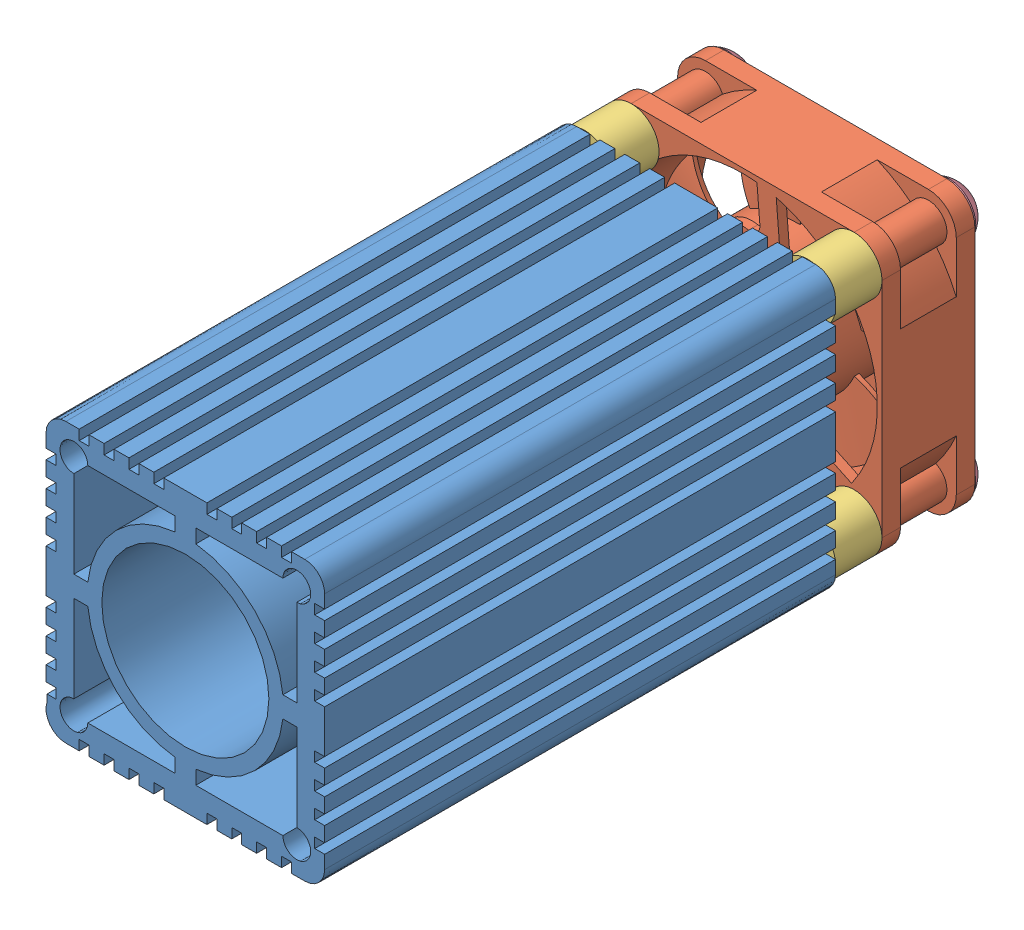
SolidWorks assembly laser host all, configuration Default. Lengths in mm.
Overall size (32.08 31.56 71.72).
10 component instances, 4 part files, 18 mates.
Components (placement in the parent):
- laser housing extrusion-1: laser housing extrusion [Default] at (39.1626 49.5405 18.2277) size (30 30 55)
- 12VDC-1.1875-X-0.375-DELTA-BOX-FAN-1: 12VDC-1.1875-X-0.375-DELTA-BOX-FAN [Default] at (39.1626 49.5405 8.2277) size (31.36 31.11 10)
- housing fan spacer-1: housing fan spacer [Default] at (27.1626 61.5405 13.2277) x (1 0 0) z (0 -1 0) size (6 5 6)
- housing fan spacer-2: housing fan spacer [Default] at (51.1626 37.5405 13.2277) x (1 0 0) z (0 -1 0) size (6 5 6)
- housing fan spacer-3: housing fan spacer [Default] at (27.1626 37.5405 13.2277) x (1 0 0) z (0 -1 0) size (6 5 6)
- housing fan spacer-4: housing fan spacer [Default] at (51.1626 61.5405 13.2277) x (1 0 0) z (0 -1 0) size (6 5 6)
- Button Head Socket Cap Screw M3-1: Button Head Socket Cap Screw M3 [M3 x 12] at (51.1626 61.5405 15.2277) x (0 0 1) z (0.923728 0.383049 0) size (13.72 5.7 5.7)
- Button Head Socket Cap Screw M3-2: Button Head Socket Cap Screw M3 [M3 x 12] at (51.1626 37.5405 15.2277) x (0 0 1) z (-0.923728 -0.383049 0) size (13.72 5.7 5.7)
- Button Head Socket Cap Screw M3-3: Button Head Socket Cap Screw M3 [M3 x 12] at (27.1626 61.5405 15.2277) x (0 0 1) z (-0.923728 -0.383049 0) size (13.72 5.7 5.7)
- Button Head Socket Cap Screw M3-4: Button Head Socket Cap Screw M3 [M3 x 12] at (27.1626 37.5405 15.2277) x (0 0 1) z (-0.923728 -0.383049 0) size (13.72 5.7 5.7)
Mates (geometry in assembly coordinates):
- Coincident1: coincident anti-aligned: plane of laser housing extrusion-1 through (52.0186 62.329 18.2277) normal (0 0 -1); plane of housing fan spacer-4 through (51.1626 61.5405 18.2277) normal (0 0 1)
- Concentric2: concentric aligned: cylinder of laser housing extrusion-1 through (51.1626 61.5405 73.2277) axis (0 0 -1) radius 1.5; cylinder of housing fan spacer-4 through (51.1626 61.5405 18.2277) axis (0 0 -1) radius 1.5
- Coincident2: coincident anti-aligned: plane of laser housing extrusion-1 through (52.0186 62.329 18.2277) normal (0 0 -1); plane of housing fan spacer-1 through (27.1626 61.5405 18.2277) normal (0 0 1)
- Concentric3: concentric aligned: cylinder of laser housing extrusion-1 through (27.1626 61.5405 73.2277) axis (0 0 -1) radius 1.5; cylinder of housing fan spacer-1 through (27.1626 61.5405 18.2277) axis (0 0 -1) radius 1.5
- Coincident3: coincident anti-aligned: plane of laser housing extrusion-1 through (52.0186 62.329 18.2277) normal (0 0 -1); plane of housing fan spacer-3 through (27.1626 37.5405 18.2277) normal (0 0 1)
- Concentric4: concentric aligned: cylinder of laser housing extrusion-1 through (27.1626 37.5405 73.2277) axis (0 0 -1) radius 1.5; cylinder of housing fan spacer-3 through (27.1626 37.5405 18.2277) axis (0 0 -1) radius 1.5
- Coincident4: coincident anti-aligned: plane of laser housing extrusion-1 through (52.0186 62.329 18.2277) normal (0 0 -1); plane of housing fan spacer-2 through (51.1626 37.5405 18.2277) normal (0 0 1)
- Concentric5: concentric aligned: cylinder of laser housing extrusion-1 through (51.1626 37.5405 73.2277) axis (0 0 -1) radius 1.5; cylinder of housing fan spacer-2 through (51.1626 37.5405 18.2277) axis (0 0 -1) radius 1.5
- Coincident5: coincident anti-aligned: plane of 12VDC-1.1875-X-0.375-DELTA-BOX-FAN-1 through (54.1626 34.5405 13.2277) normal (0 0 1); plane of housing fan spacer-3 through (27.1626 37.5405 13.2277) normal (0 0 -1)
- Concentric7: concentric anti-aligned: cylinder of 12VDC-1.1875-X-0.375-DELTA-BOX-FAN-1 through (27.1626 37.5405 3.2277) axis (0 0 1) radius 1.6; cylinder of housing fan spacer-3 through (27.1626 37.5405 18.2277) axis (0 0 -1) radius 1.5
- Coincident6: coincident anti-aligned: plane of 12VDC-1.1875-X-0.375-DELTA-BOX-FAN-1 through (54.1626 34.5405 3.2277) normal (0 0 -1); plane of Button Head Socket Cap Screw M3-1 through (52.2543 58.9079 3.2277) normal (0 0 1)
- Coincident7: coincident anti-aligned: plane of 12VDC-1.1875-X-0.375-DELTA-BOX-FAN-1 through (54.1626 34.5405 3.2277) normal (0 0 -1); plane of Button Head Socket Cap Screw M3-2 through (50.0709 40.1732 3.2277) normal (0 0 1)
- Coincident8: coincident anti-aligned: plane of 12VDC-1.1875-X-0.375-DELTA-BOX-FAN-1 through (54.1626 34.5405 3.2277) normal (0 0 -1); plane of Button Head Socket Cap Screw M3-4 through (26.0709 40.1732 3.2277) normal (0 0 1)
- Coincident10: coincident anti-aligned: plane of 12VDC-1.1875-X-0.375-DELTA-BOX-FAN-1 through (54.1626 34.5405 3.2277) normal (0 0 -1); plane of Button Head Socket Cap Screw M3-3 through (26.0709 64.1732 3.2277) normal (0 0 1)
- Concentric8: concentric aligned: cylinder of 12VDC-1.1875-X-0.375-DELTA-BOX-FAN-1 through (27.1626 37.5405 3.2277) axis (0 0 1) radius 1.6; cylinder of Button Head Socket Cap Screw M3-4 through (27.1626 37.5405 3.2277) axis (0 0 1) radius 1.5
- Concentric9: concentric aligned: cylinder of 12VDC-1.1875-X-0.375-DELTA-BOX-FAN-1 through (51.1626 37.5405 3.2277) axis (0 0 1) radius 1.6; cylinder of Button Head Socket Cap Screw M3-2 through (51.1626 37.5405 3.2277) axis (0 0 1) radius 1.5
- Concentric11: concentric aligned: cylinder of 12VDC-1.1875-X-0.375-DELTA-BOX-FAN-1 through (51.1626 61.5405 3.2277) axis (0 0 1) radius 1.6; cylinder of Button Head Socket Cap Screw M3-1 through (51.1626 61.5405 3.2277) axis (0 0 1) radius 1.5
- Concentric12: concentric aligned: cylinder of 12VDC-1.1875-X-0.375-DELTA-BOX-FAN-1 through (27.1626 61.5405 3.2277) axis (0 0 1) radius 1.6; cylinder of Button Head Socket Cap Screw M3-3 through (27.1626 61.5405 3.2277) axis (0 0 1) radius 1.5
